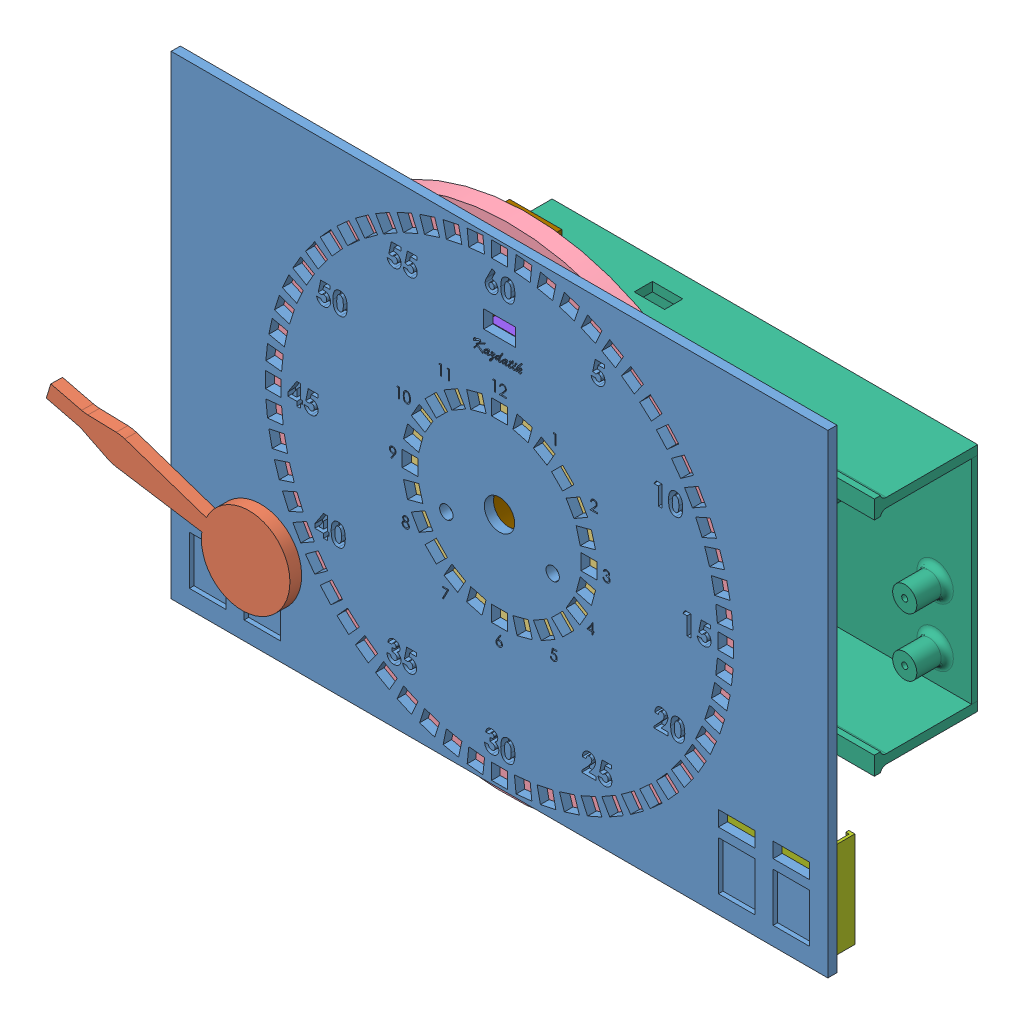
SolidWorks assembly ComplexHour, configuration Default. Lengths in mm.
Overall size (220.4 178.74 100.8).
9 component instances, 9 part files, 21 mates.
Components (placement in the parent):
- Plywood-1: Plywood [Default] at (-34.3772 31.408 173.1073) size (216 156 3)
- rucicka(2)-1: rucicka(2) [Default] at (28.8201 93.2683 214.8112) x (-0.258126 -0.964473 0.056238) z (-0.032162 -0.0496 -0.998251) size (28.2 80 10)
- BoxForLed24-1: BoxForLed24 [Default] at (73.6228 109.408 173.1073) x (-0.103139 -0.994664 0.002416) z (0.000029 -0.002432 -0.999997) size (72 72 6)
- BoxForLed60-1: BoxForLed60 [Default] at (73.6228 109.408 173.1073) x (-0.103139 -0.994664 0.002416) z (0.000029 -0.002432 -0.999997) size (162.8 162.8 6)
- BoxForTouchSensorsSecondSide-1: BoxForTouchSensorsSecondSide [Default] at (2.7228 31.408 173.1073) x (-1 0 0) z (0 0 -1) size (97.15 34.5 11)
- Stand-1: Stand [Výchozí] at (170.8228 74.908 116.0073) x (0 1 0) z (0 0 1) size (79 140 34)
- ovlA20-1: ovlA20 [Default] at (14.2228 31.408 173.1073) x (-1 0 0) z (0 0 -1) size (97.15 34.5 11)
- HolderForIrSensor-1: HolderForIrSensor [Default] at (83.4228 154.8446 173.1073) x (-1 0 0) z (0 0 -1) size (19.6 5 4.8)
- EngineBox-1: EngineBox [Default] at (37.4228 73.408 151.2073) size (85.6 160 29)
Mates (geometry in assembly coordinates):
- Coincident3: coincident: point of PreklizkaFinal-1
- Coincident4: coincident: line of PreklizkaFinal-1 through (181.6228 31.408 173.1073) axis (0 1 0)
- Coincident5: coincident: line of PreklizkaFinal-1 through (-34.3772 31.408 173.1073) axis (1 0 0)
- Coincident7: coordinate: point of KrabickaLedky24-1; point of KrabickaLedky60-1
- Coincident9: coincident: unknown of KrabickaLedky24-1
- Coincident12: coincident anti-aligned: plane of PreklizkaFinal-1 through (-34.3772 31.408 173.1073) normal (0 0 -1); plane of motorkrabicka2-1 through (39.5912 75.808 173.1073) normal (0 0 1)
- Coincident14: coincident aligned: line of PreklizkaFinal-1 through (-34.3772 187.408 173.1073) axis (1 0 0); line of motorkrabicka2-1 through (65.9912 187.408 173.1073) axis (1 0 0)
- Coincident18: coincident anti-aligned: plane of PreklizkaFinal-1 through (-34.3772 31.408 173.1073) normal (0 0 -1); plane of motorkrabicka3-1 through (38.3728 75.5123 173.1073) normal (0 0 1)
- Parallel1: parallel anti-aligned: line of PreklizkaFinal-1 through (-34.3772 31.408 173.1073) axis (0 1 0); line of motorkrabicka3-1 through (33.7728 150.1166 173.1073) axis (0 -1 0)
- Parallel2: parallel aligned: line of PreklizkaFinal-1 through (-34.3772 187.408 173.1073) axis (1 0 0); line of motorkrabicka3-1 through (64.7728 187.1123 163.1073) axis (1 0 0)
- Coincident26: coincident anti-aligned: plane of motorkrabicka3-1 through (121.7728 143.4123 148.9073) normal (0 0 -1); plane of stojan-v6-1 through (30.8228 143.408 150.0073) normal (0 0 1)
- Parallel3: parallel aligned: line of PreklizkaFinal-1 through (-34.3772 187.408 173.1073) axis (1 0 0); line of motorkrabicka3-1 through (31.7728 152.1123 144.1073) axis (1 0 0)
- Parallel5: parallel anti-aligned: line of PreklizkaFinal-1 through (-34.3772 187.408 173.1073) axis (1 0 0); line of motorkrabicka3-1 through (81.9728 187.1123 166.9073) axis (-1 0 0)
- Coincident39: coincident anti-aligned: line of motorkrabicka3-1 through (81.3728 63.908 173.1073) axis (0 0 -1); line of ovlA20-1 through (81.3728 63.908 162.1073) axis (0 0 1)
- Coincident41: coincident anti-aligned: plane of stojan-v6-1 through (30.8228 143.408 150.0073) normal (0 0 1); plane of motorkrabicka4-1 through (120.8228 143.408 150.0073) normal (0 0 -1)
- Coincident42: coincident anti-aligned: plane of stojan-v6-1 through (30.8228 76.408 150.0073) normal (0 0 1); plane of motorkrabicka4-1 through (120.8228 77.008 150.0073) normal (0 0 -1)
- Parallel8: parallel anti-aligned: line of stojan-v6-1 through (170.8228 147.908 116.0073) axis (-1 0 0); line of motorkrabicka4-1 through (30.8228 154.008 145.2073) axis (1 0 0)
- Coincident46: coincident anti-aligned: line of stojan-v6-1 through (30.8228 70.408 150.0073) axis (0 0 -1); line of motorkrabicka4-1 through (30.8228 70.408 147.6073) axis (0 0 1)
- Coincident47: coincident anti-aligned: plane of PreklizkaFinal-1 through (-34.3772 31.408 173.1073) normal (0 0 -1); plane of DrzakIRSenzor-1 through (83.4228 154.8446 173.1073) normal (0 0 1)
- Coincident51: coincident: line of DrzakIRSenzor-1 through (65.0228 159.8446 168.3073) axis (0 -1 0); plane of motorkrabicka4-1 through (65.0228 73.408 173.2073) normal (-1 0 0)
- Coincident52: coincident anti-aligned: circle of PreklizkaFinal-1; circle of motorkrabicka4-1
